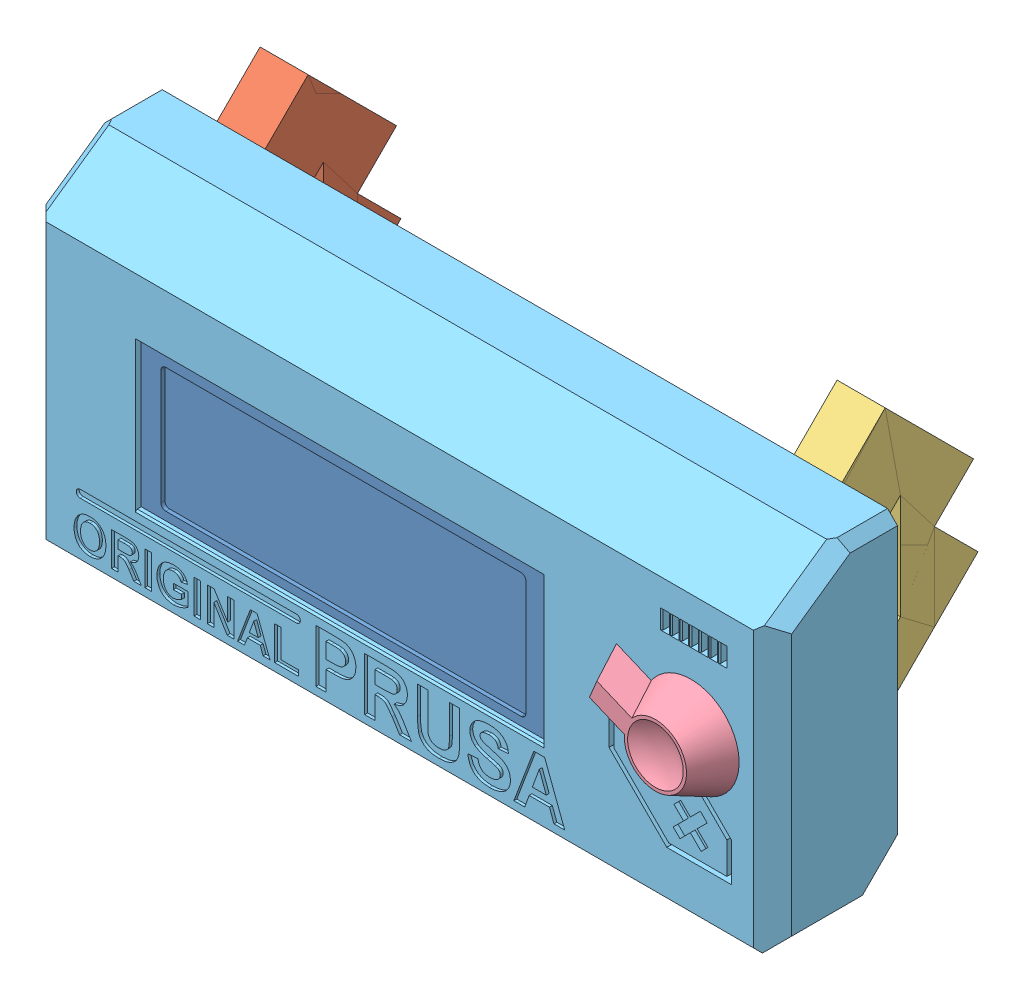
SolidWorks assembly LCD Assembly, configuration Default. Lengths in mm.
Overall size (155 84.29 80.03).
5 component instances, 5 part files, 11 mates.
Components (placement in the parent):
- LCD Board-1: LCD Board [Default] at (45.5138 89.6171 111.3378) size (150 63 29.71)
- lcd-supports1-1: lcd-supports1 [Default] at (-9.0362 59.8671 105.6378) x (0 -0.707107 0.707107) z (-1 0 0) size (65.69 47.48 20)
- lcd-supports2-1: lcd-supports2 [Default] at (110.9738 59.8671 105.6378) x (0 -0.707107 0.707107) z (-1 0 0) size (65.69 47.48 10)
- LCD-KNOB-1: LCD-KNOB [Default] at (104.2929 89.8433 126.2378) x (-0.386654 -0.922225 0) z (0 0 1) size (20 27.64 8.79)
- LCD-cover-ORIGINAL-MK3(R2)-1: LCD-cover-ORIGINAL-MK3(R2) [Default] at (45.2638 108.0671 124.7378) x (1 0 0) z (0 0 -1) size (155 70 26.06)
Mates (geometry in assembly coordinates):
- Coincident1: coincident anti-aligned: plane of LCD Board-1 through (45.5138 89.6171 109.6378) normal (0 0 -1); plane of lcd-supports1-1 through (-4.0362 116.3671 109.6378) normal (0 0 1)
- Coincident5: coincident anti-aligned: plane of LCD Board-1 through (45.5138 89.6171 109.6378) normal (0 0 -1); plane of lcd-supports2-1 through (111.9738 61.3671 109.6378) normal (0 0 1)
- Parallel1: parallel anti-aligned: plane of LCD Board-1 through (-29.4862 62.1171 109.6378) normal (0 -1 0); plane of lcd-supports2-1 through (111.9738 61.3671 109.6378) normal (0 1 0)
- Parallel2: parallel anti-aligned: plane of LCD Board-1 through (-29.4862 62.1171 109.6378) normal (0 -1 0); plane of lcd-supports1-1 through (-8.0362 61.3671 109.6378) normal (0 1 0)
- Coincident7: coincident anti-aligned: plane of LCD Board-1 through (45.5138 89.6171 111.3378) normal (0 1 0); plane of lcd-supports1-1 through (-9.0362 89.6171 105.6378) normal (0 -1 0)
- Coincident8: coincident anti-aligned: plane of LCD Board-1 through (45.5138 89.6171 111.3378) normal (0 1 0); plane of lcd-supports2-1 through (110.9738 89.6171 105.6378) normal (0 -1 0)
- Concentric4: concentric anti-aligned: cylinder of LCD Board-1 through (107.8138 88.3671 122.5378) axis (0 0 -1) radius 3; circle of LCD-KNOB-1
- Coincident10: coincident anti-aligned: plane of LCD Board-1 through (45.5138 89.6171 130.5378) normal (0 0 1); plane of LCD-KNOB-1 through (107.8138 88.3671 130.5378) normal (0 0 -1)
- Concentric5: concentric aligned: circle of LCD Board-1; circle of LCD-cover-ORIGINAL-MK3(R2)-1
- Parallel3: parallel aligned: plane of LCD Board-1 through (-29.4862 117.1171 109.6378) normal (-1 0 0); plane of LCD-cover-ORIGINAL-MK3(R2)-1 through (-31.7362 122.7671 124.7378) normal (-1 0 0)
- Coincident11: coincident anti-aligned: plane of LCD Board-1 through (45.5138 89.6171 123.5378) normal (0 0 1); plane of LCD-cover-ORIGINAL-MK3(R2)-1 through (-16.2362 107.0671 123.5378) normal (0 0 -1)
